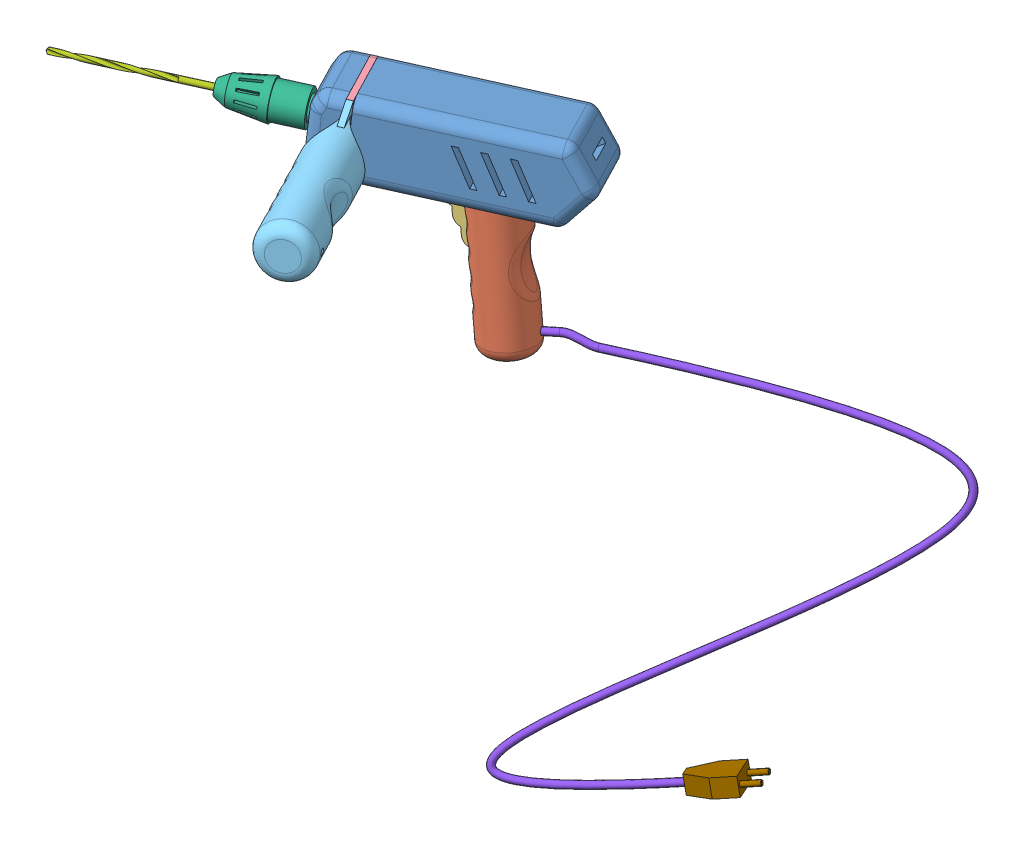
SolidWorks assembly PowerDrillI, configuration Default. Lengths in mm.
Overall size (631.22 489.96 385.82).
9 component instances, 9 part files, 18 mates.
Components (placement in the parent):
- body-2: body [Default] at (72.9871 127.7914 136.1233) x (0.865483 -0.072857 -0.495613) z (0.500931 0.120407 0.857071) size (197.69 64.52 70)
- handle-2: handle [Default] at (119.1866 101.9555 154.307) x (0.852815 0.10017 -0.512517) z (0.147563 -0.987658 0.052507) size (45.68 45 121.93)
- triger-1: triger [Default] at (107.8799 58.4933 166.3019) x (-0.500931 -0.120407 -0.857071) z (0.852815 0.10017 -0.512517) size (15 44.12 15)
- support-1: support [Default] at (20.6215 101.9864 178.3685) x (0.865483 -0.072857 -0.495613) z (0.00704 0.991038 -0.133393) size (5 70 64.5)
- handle - support-1: handle - support [Default] at (72.1432 145.483 262.4771) x (0.865483 -0.072857 -0.495613) z (0.50089 0.11196 0.858239) size (45.68 64.5 162.73)
- chalck-1: chalck [Default] at (20.762 131.7872 199.9852) x (0.865483 -0.072857 -0.495613) z (0.322103 -0.676786 0.661975) size (88 32.58 32.58)
- drillbit-1: drillbit [Default] at (-148.4766 151.9997 302.9979) x (-0.099286 0.944791 -0.312269) z (-0.491001 -0.319471 -0.810467) size (9.13 120.25 9.17)
- wire-2: wire [Default] at (134.5331 -0.7609 159.7677) x (-0.462848 -0.309487 -0.830656) z (-0.852815 -0.10017 0.512517) size (6 313.64 335.27)
- plug-1: plug [Default] at (331.9313 -259.418 139.5276) x (-0.49471 -0.214781 -0.842099) z (0.292288 -0.953652 0.071522) size (30 54.34 15)
Mates (geometry in assembly coordinates):
- Concentric3: concentric anti-aligned: cylinder of body-2 through (116.0675 122.8317 153.1972) axis (0.147563 -0.987658 0.052507) radius 7.3861; cylinder of handle-2 through (122.5805 79.2394 155.5147) axis (-0.147563 0.987658 -0.052507) radius 7.5
- Coincident1: coincident anti-aligned: plane of body-2 through (180.6752 98.5001 158.9715) normal (-0.002768 -0.990047 0.140707); plane of handle-2 through (137.6144 92.8772 118.5597) normal (0.002768 0.990047 -0.140707)
- Parallel2: parallel aligned: plane of body-2 through (72.9871 127.7914 136.1233) normal (-0.500931 -0.120407 -0.857071); plane of triger-1 through (104.1229 57.5902 159.8738) normal (-0.500931 -0.120407 -0.857071)
- Coincident4: coincident anti-aligned: plane of body-2 through (180.6752 98.5001 158.9715) normal (-0.002768 -0.990047 0.140707); plane of triger-1 through (92.6905 102.9804 188.7647) normal (0.002768 0.990047 -0.140707)
- Width1: width aligned: plane of body-2 through (72.9871 127.7914 136.1233) normal (-0.500931 -0.120407 -0.857071); plane of body-2 through (108.0523 136.2199 196.1183) normal (0.500931 0.120407 0.857071); plane of triger-1 through (104.1229 57.5902 159.8738) normal (-0.500931 -0.120407 -0.857071); plane of triger-1 through (111.6369 59.3963 172.7299) normal (0.500931 0.120407 0.857071)
- Distance2: distance = 90 mm: line of triger-1 through (84.8207 99.6598 165.2452) axis (0.500931 0.120407 0.857071); plane of body-2 through (28.2512 123.612 244.5309) normal (-0.865483 0.072857 0.495613)
- Coincident13: coincident anti-aligned: line of support-1 through (50.171 173.1477 225.0846) axis (-0.00704 -0.991038 0.133393); line of handle - support-1 through (50.1014 163.347 226.4038) axis (0.00704 0.991038 -0.133393)
- Coincident14: coincident aligned: line of support-1 through (50.171 173.1477 225.0846) axis (0.865483 -0.072857 -0.495613); line of handle - support-1 through (50.171 173.1477 225.0846) axis (0.865483 -0.072857 -0.495613)
- Concentric6: concentric aligned: cylinder of body-2 through (36.7367 136.4083 196.9368) axis (-0.865483 0.072857 0.495613) radius 10; cylinder of chalck-1 through (-27.309 141.7997 233.6121) axis (-0.865483 0.072857 0.495613) radius 10
- Distance3: distance = 5 mm anti-aligned: plane of chalck-1 through (10.2813 146.284 219.906) normal (0.865483 -0.072857 -0.495613); plane of body-2 through (28.2512 123.612 244.5309) normal (-0.865483 0.072857 0.495613)
- Concentric7: concentric anti-aligned: cylinder of chalck-1 through (-47.2151 143.4755 245.0112) axis (0.865483 -0.072857 -0.495613) radius 2.5; cylinder of drillbit-1 through (-44.6187 143.2569 243.5244) axis (-0.865483 0.072857 0.495613) radius 2.5
- Distance5: distance = 20 mm anti-aligned: plane of chalck-1 through (-25.314 145.6091 236.536) normal (-0.865483 0.072857 0.495613); plane of drillbit-1 through (-44.6187 143.2569 243.5244) normal (0.865483 -0.072857 -0.495613)
- Concentric11: concentric anti-aligned: cylinder of handle-2 through (228.3427 10.2578 103.3909) axis (-0.852815 -0.10017 0.512517) radius 3; cylinder of wire-2 through (134.5331 -0.7609 159.7677) axis (0.852815 0.10017 -0.512517) radius 3
- Coincident25: coincident anti-aligned: circle of handle-2; circle of wire-2
- Distance7: distance = 0 mm anti-aligned: plane of support-1 through (19.4361 164.9462 162.5298) normal (0.865483 -0.072857 -0.495613); plane of body-2 through (36.7367 136.4083 196.9368) normal (-0.865483 0.072857 0.495613)
- Concentric14: concentric anti-aligned: cylinder of body-2 through (32.4093 136.7726 199.4149) axis (0.865483 -0.072857 -0.495613) radius 21.9509; cylinder of support-1 through (41.0641 136.044 194.4588) axis (-0.865483 0.072857 0.495613) radius 21.9509
- Coincident26: coincident aligned: circle of wire-2; circle of plug-1
- Lock1: lock: unknown of wire-2; unknown of plug-1
